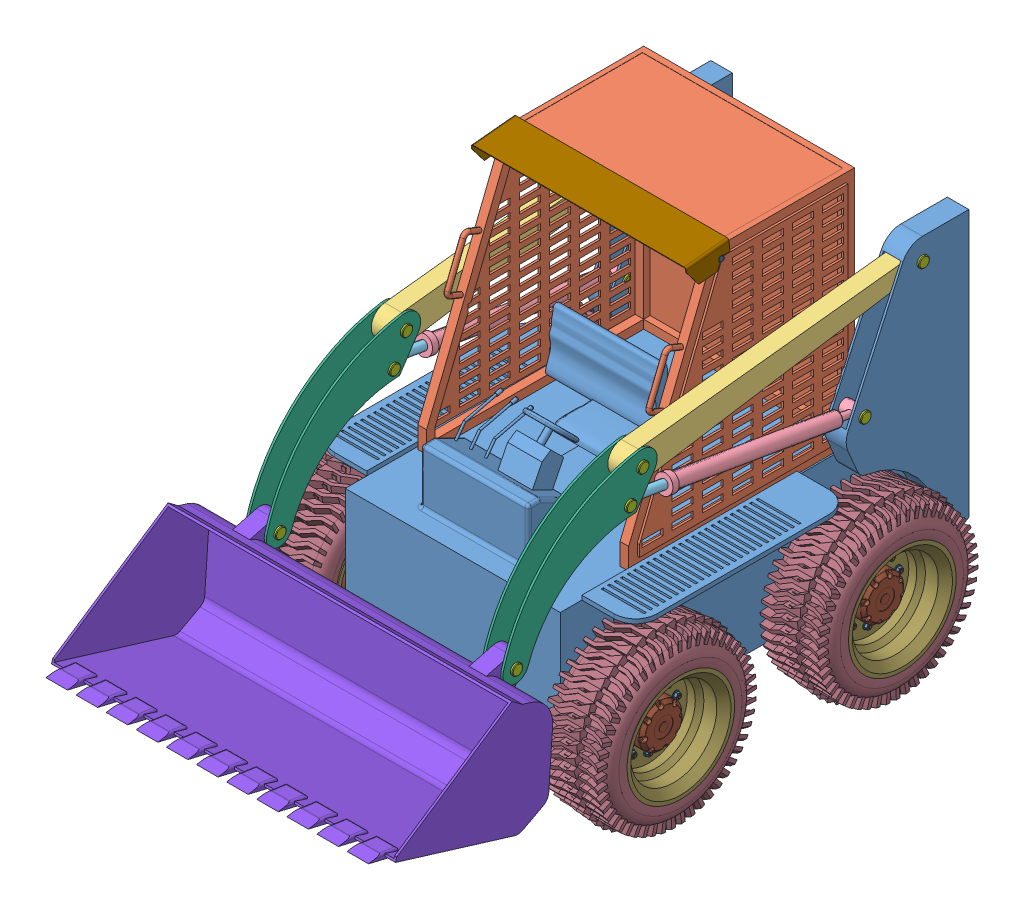
SolidWorks assembly MAINASSEM, configuration Default. Lengths in mm.
Overall size (1661.42 2117.38 2991.67).
82 component instances, 14 part files, 36 mates.
Components (placement in the parent):
- body-1: body [Default] at (611.6041 142.7188 2334.3513) size (1500 1375 1850)
- Part2-1: Part2 [Default] at (614.3973 1786.0912 2050.7348) size (1000 1100 1050)
- LIFTINGARM2-1: LIFTINGARM2 [Default] at (1161.6041 1247.7203 2057.6803) x (0 0.125849 -0.992049) z (1 0 0) size (1424.96 140 80)
- cylinderbody-1: cylinderbody [Default] at (1161.6041 1066.1236 1944.5095) x (0 -0.169943 -0.985454) z (0 -0.985454 0.169943) size (935 91.5 85)
- cylinder-1: cylinder [Default] at (1170.6016 1101.0933 2172.4592) x (0 -0.169943 -0.985454) z (1 0 0) size (960 60 80)
- LIFTING ARM-1: LIFTING ARM [Default] at (1206.6041 887.1212 2209.3761) x (0 -0.052276 -0.998633) z (1 0 0) size (690 680 10)
- LIFTING ARM-2: LIFTING ARM [Default] at (1116.6041 887.1212 2209.3761) x (0 -0.052276 -0.998633) z (1 0 0) size (690 680 10)
- pin-1: pin [Default] at (1155.3766 921.3702 1094.0266) x (0 -0.804682 0.593706) z (-1 0 0) size (50 50 120)
- pin-2: pin [Default] at (1167.8316 1418.2021 812.5835) x (0 0 -1) z (1 0 0) size (50 50 120)
- pin-3: pin [Default] at (1167.8316 1242.0493 2115.7317) x (0 0 -1) z (1 0 0) size (50 50 120)
- pin-4: pin [Default] at (1167.8316 1114.8408 2172.4592) x (0 0 -1) z (1 0 0) size (50 50 120)
- cylinderbody-2: cylinderbody [Default] at (61.6041 1057.6932 1945.9633) x (0 -0.169943 -0.985454) z (0 0.985454 -0.169943) size (935 91.5 85)
- LIFTINGARM2-2: LIFTINGARM2 [Default] at (61.6041 1247.7203 2057.6803) x (0 0.125849 -0.992049) z (1 0 0) size (1424.96 140 80)
- LIFTING ARM-3: LIFTING ARM [Default] at (16.6041 887.1212 2209.3761) x (0 -0.052276 -0.998633) z (1 0 0) size (690 680 10)
- LIFTING ARM-4: LIFTING ARM [Default] at (106.6041 887.1212 2209.3761) x (0 -0.052276 -0.998633) z (1 0 0) size (690 680 10)
- pin-5: pin [Default] at (67.8316 1242.0493 2115.7317) x (0 0 -1) z (1 0 0) size (50 50 120)
- pin-6: pin [Default] at (67.8316 1114.8408 2172.4592) x (0 0 -1) z (1 0 0) size (50 50 120)
- cylinder-2: cylinder [Default] at (52.6065 1101.0933 2172.4592) x (0 -0.169943 -0.985454) z (1 0 0) size (960 60 80)
- pin-7: pin [Default] at (55.3766 921.3702 1094.0266) x (0 -0.804682 0.593706) z (-1 0 0) size (50 50 120)
- pin-8: pin [Default] at (67.8316 1418.2021 812.5835) x (0 0 -1) z (1 0 0) size (50 50 120)
- bucket-1: bucket [Default] at (611.6041 787.1742 4757.017) x (1 0 0) z (0 0.292263 0.956338) size (1600 584.7 778.71)
- pin-9: pin [Default] at (1155.3766 722.0758 2703.7178) x (0 -0.000008 1) z (-1 0 0) size (50 50 120)
- pin-10: pin [Default] at (67.8316 722.0758 2703.7177) x (0 0 -1) z (1 0 0) size (50 50 120)
- cabin cap-1: cabin cap [Default] at (-264.117 1843.1629 1712.7348) x (1 0 0) z (0 -0.097432 0.995242) size (1000 100 200)
- cabinpin-1: cabinpin [Default] at (1152.5547 1805.3715 1646.3924) size (20.08 26 26)
- cabinpin-2: cabinpin [Default] at (70.2399 1772.6095 1623.9541) x (-1 0 0) z (0 -0.93241 0.361403) size (20.08 26 26)
- TYRE SUBASSEMBLY-1: TYRE SUBASSEMBLY [Default] at (1011.6041 44.44 2124.6318) x (1 0 0) z (0 0.62928 0.777179) size (370 785.47 785.35)
  - axle-1: axle [Default] at (218.9443 340.3251 180.7776) size (290.15 300 300)
  - rim-1: rim [Default] at (195.7643 350.8233 180.7776) size (310 500 500)
  - TYRE-1: TYRE [Default] at (277.7643 397.9842 180.7776) size (305.48 785.47 785.35)
  - hex flange nut_am-1: hex flange nut_am [B18.2.2.4M - Hex flange nut, M12 x 1.75 --N] at (292.7118 116.3804 57.1403) x (0 -0.380112 -0.92494) z (1 0 0) size (26 26 12)
  - hex flange nut_am-5: hex flange nut_am [B18.2.2.4M - Hex flange nut, M16 x 2 --N] at (296.7118 196.7248 57.1403) x (0 0 -1) z (1 0 0) size (34.5 34.5 16)
  - hex flange nut_am-6: hex flange nut_am [B18.2.2.4M - Hex flange nut, M16 x 2 --N] at (296.7118 261.7248 104.3655) x (0 0 -1) z (1 0 0) size (34.5 34.5 16)
  - hex flange nut_am-7: hex flange nut_am [B18.2.2.4M - Hex flange nut, M16 x 2 --N] at (296.7118 286.5526 180.7776) x (0 0 -1) z (1 0 0) size (34.5 34.5 16)
  - hex flange nut_am-8: hex flange nut_am [B18.2.2.4M - Hex flange nut, M16 x 2 --N] at (296.7118 261.7248 257.1897) x (0 0 -1) z (1 0 0) size (34.5 34.5 16)
  - hex flange nut_am-9: hex flange nut_am [B18.2.2.4M - Hex flange nut, M16 x 2 --N] at (296.7118 196.7248 304.415) x (0 0 -1) z (1 0 0) size (34.5 34.5 16)
  - hex flange nut_am-10: hex flange nut_am [B18.2.2.4M - Hex flange nut, M16 x 2 --N] at (296.7118 116.3804 304.415) x (0 0 -1) z (1 0 0) size (34.5 34.5 16)
  - hex flange nut_am-11: hex flange nut_am [B18.2.2.4M - Hex flange nut, M16 x 2 --N] at (296.7118 51.3804 257.1897) x (0 0 -1) z (1 0 0) size (34.5 34.5 16)
  - hex flange nut_am-12: hex flange nut_am [B18.2.2.4M - Hex flange nut, M16 x 2 --N] at (296.7118 26.5526 180.7776) x (0 0 -1) z (1 0 0) size (34.5 34.5 16)
  - hex flange nut_am-13: hex flange nut_am [B18.2.2.4M - Hex flange nut, M16 x 2 --N] at (296.7118 51.3804 104.3655) x (0 0 -1) z (1 0 0) size (34.5 34.5 16)
- TYRE SUBASSEMBLY-2: TYRE SUBASSEMBLY [Default] at (1011.6041 333.024 1369.7734) x (1 0 0) z (0 0.47024 -0.882539) size (370 785.47 785.35)
  - axle-1: axle [Default] at (218.9443 340.3251 180.7776) size (290.15 300 300)
  - rim-1: rim [Default] at (195.7643 350.8233 180.7776) size (310 500 500)
  - TYRE-1: TYRE [Default] at (277.7643 397.9842 180.7776) size (305.48 785.47 785.35)
  - hex flange nut_am-1: hex flange nut_am [B18.2.2.4M - Hex flange nut, M12 x 1.75 --N] at (292.7118 116.3804 57.1403) x (0 -0.380112 -0.92494) z (1 0 0) size (26 26 12)
  - hex flange nut_am-5: hex flange nut_am [B18.2.2.4M - Hex flange nut, M16 x 2 --N] at (296.7118 196.7248 57.1403) x (0 0 -1) z (1 0 0) size (34.5 34.5 16)
  - hex flange nut_am-6: hex flange nut_am [B18.2.2.4M - Hex flange nut, M16 x 2 --N] at (296.7118 261.7248 104.3655) x (0 0 -1) z (1 0 0) size (34.5 34.5 16)
  - hex flange nut_am-7: hex flange nut_am [B18.2.2.4M - Hex flange nut, M16 x 2 --N] at (296.7118 286.5526 180.7776) x (0 0 -1) z (1 0 0) size (34.5 34.5 16)
  - hex flange nut_am-8: hex flange nut_am [B18.2.2.4M - Hex flange nut, M16 x 2 --N] at (296.7118 261.7248 257.1897) x (0 0 -1) z (1 0 0) size (34.5 34.5 16)
  - hex flange nut_am-9: hex flange nut_am [B18.2.2.4M - Hex flange nut, M16 x 2 --N] at (296.7118 196.7248 304.415) x (0 0 -1) z (1 0 0) size (34.5 34.5 16)
  - hex flange nut_am-10: hex flange nut_am [B18.2.2.4M - Hex flange nut, M16 x 2 --N] at (296.7118 116.3804 304.415) x (0 0 -1) z (1 0 0) size (34.5 34.5 16)
  - hex flange nut_am-11: hex flange nut_am [B18.2.2.4M - Hex flange nut, M16 x 2 --N] at (296.7118 51.3804 257.1897) x (0 0 -1) z (1 0 0) size (34.5 34.5 16)
  - hex flange nut_am-12: hex flange nut_am [B18.2.2.4M - Hex flange nut, M16 x 2 --N] at (296.7118 26.5526 180.7776) x (0 0 -1) z (1 0 0) size (34.5 34.5 16)
  - hex flange nut_am-13: hex flange nut_am [B18.2.2.4M - Hex flange nut, M16 x 2 --N] at (296.7118 51.3804 104.3655) x (0 0 -1) z (1 0 0) size (34.5 34.5 16)
- TYRE SUBASSEMBLY-4: TYRE SUBASSEMBLY [Default] at (211.6041 287.7784 1927.6012) x (-1 0 0) z (0 0.62928 0.777179) size (370 785.47 785.35)
  - axle-1: axle [Default] at (218.9443 340.3251 180.7776) size (290.15 300 300)
  - rim-1: rim [Default] at (195.7643 350.8233 180.7776) size (310 500 500)
  - TYRE-1: TYRE [Default] at (277.7643 397.9842 180.7776) size (305.48 785.47 785.35)
  - hex flange nut_am-1: hex flange nut_am [B18.2.2.4M - Hex flange nut, M12 x 1.75 --N] at (292.7118 116.3804 57.1403) x (0 -0.380112 -0.92494) z (1 0 0) size (26 26 12)
  - hex flange nut_am-5: hex flange nut_am [B18.2.2.4M - Hex flange nut, M16 x 2 --N] at (296.7118 196.7248 57.1403) x (0 0 -1) z (1 0 0) size (34.5 34.5 16)
  - hex flange nut_am-6: hex flange nut_am [B18.2.2.4M - Hex flange nut, M16 x 2 --N] at (296.7118 261.7248 104.3655) x (0 0 -1) z (1 0 0) size (34.5 34.5 16)
  - hex flange nut_am-7: hex flange nut_am [B18.2.2.4M - Hex flange nut, M16 x 2 --N] at (296.7118 286.5526 180.7776) x (0 0 -1) z (1 0 0) size (34.5 34.5 16)
  - hex flange nut_am-8: hex flange nut_am [B18.2.2.4M - Hex flange nut, M16 x 2 --N] at (296.7118 261.7248 257.1897) x (0 0 -1) z (1 0 0) size (34.5 34.5 16)
  - hex flange nut_am-9: hex flange nut_am [B18.2.2.4M - Hex flange nut, M16 x 2 --N] at (296.7118 196.7248 304.415) x (0 0 -1) z (1 0 0) size (34.5 34.5 16)
  - hex flange nut_am-10: hex flange nut_am [B18.2.2.4M - Hex flange nut, M16 x 2 --N] at (296.7118 116.3804 304.415) x (0 0 -1) z (1 0 0) size (34.5 34.5 16)
  - hex flange nut_am-11: hex flange nut_am [B18.2.2.4M - Hex flange nut, M16 x 2 --N] at (296.7118 51.3804 257.1897) x (0 0 -1) z (1 0 0) size (34.5 34.5 16)
  - hex flange nut_am-12: hex flange nut_am [B18.2.2.4M - Hex flange nut, M16 x 2 --N] at (296.7118 26.5526 180.7776) x (0 0 -1) z (1 0 0) size (34.5 34.5 16)
  - hex flange nut_am-13: hex flange nut_am [B18.2.2.4M - Hex flange nut, M16 x 2 --N] at (296.7118 51.3804 104.3655) x (0 0 -1) z (1 0 0) size (34.5 34.5 16)
- TYRE SUBASSEMBLY-5: TYRE SUBASSEMBLY [Default] at (211.6041 56.697 1222.539) x (-1 0 0) z (0 0.47024 -0.882539) size (370 785.47 785.35)
  - axle-1: axle [Default] at (218.9443 340.3251 180.7776) size (290.15 300 300)
  - rim-1: rim [Default] at (195.7643 350.8233 180.7776) size (310 500 500)
  - TYRE-1: TYRE [Default] at (277.7643 397.9842 180.7776) size (305.48 785.47 785.35)
  - hex flange nut_am-1: hex flange nut_am [B18.2.2.4M - Hex flange nut, M12 x 1.75 --N] at (292.7118 116.3804 57.1403) x (0 -0.380112 -0.92494) z (1 0 0) size (26 26 12)
  - hex flange nut_am-5: hex flange nut_am [B18.2.2.4M - Hex flange nut, M16 x 2 --N] at (296.7118 196.7248 57.1403) x (0 0 -1) z (1 0 0) size (34.5 34.5 16)
  - hex flange nut_am-6: hex flange nut_am [B18.2.2.4M - Hex flange nut, M16 x 2 --N] at (296.7118 261.7248 104.3655) x (0 0 -1) z (1 0 0) size (34.5 34.5 16)
  - hex flange nut_am-7: hex flange nut_am [B18.2.2.4M - Hex flange nut, M16 x 2 --N] at (296.7118 286.5526 180.7776) x (0 0 -1) z (1 0 0) size (34.5 34.5 16)
  - hex flange nut_am-8: hex flange nut_am [B18.2.2.4M - Hex flange nut, M16 x 2 --N] at (296.7118 261.7248 257.1897) x (0 0 -1) z (1 0 0) size (34.5 34.5 16)
  - hex flange nut_am-9: hex flange nut_am [B18.2.2.4M - Hex flange nut, M16 x 2 --N] at (296.7118 196.7248 304.415) x (0 0 -1) z (1 0 0) size (34.5 34.5 16)
  - hex flange nut_am-10: hex flange nut_am [B18.2.2.4M - Hex flange nut, M16 x 2 --N] at (296.7118 116.3804 304.415) x (0 0 -1) z (1 0 0) size (34.5 34.5 16)
  - hex flange nut_am-11: hex flange nut_am [B18.2.2.4M - Hex flange nut, M16 x 2 --N] at (296.7118 51.3804 257.1897) x (0 0 -1) z (1 0 0) size (34.5 34.5 16)
  - hex flange nut_am-12: hex flange nut_am [B18.2.2.4M - Hex flange nut, M16 x 2 --N] at (296.7118 26.5526 180.7776) x (0 0 -1) z (1 0 0) size (34.5 34.5 16)
  - hex flange nut_am-13: hex flange nut_am [B18.2.2.4M - Hex flange nut, M16 x 2 --N] at (296.7118 51.3804 104.3655) x (0 0 -1) z (1 0 0) size (34.5 34.5 16)
Mates (geometry in assembly coordinates):
- Coincident2: coincident anti-aligned: plane of body-1 through (1111.6041 731.3066 2396.6129) normal (0 1 0); plane of Part2-1 through (1104.3973 731.3066 1021.3924) normal (0 -1 0)
- Concentric1: concentric anti-aligned: cylinder of body-1 through (-128.3959 1404.4546 812.5835) axis (1 0 0) radius 20; cylinder of LIFTINGARM2-1 through (1201.6041 1404.4546 812.5835) axis (-1 0 0) radius 20
- Coincident3: coincident anti-aligned: plane of body-1 through (1121.6041 142.7188 2334.3513) normal (1 0 0); plane of LIFTINGARM2-1 through (1121.6041 1228.3018 2115.7317) normal (-1 0 0)
- Concentric2: concentric anti-aligned: cylinder of body-1 through (-128.3959 913.2082 1082.9643) axis (1 0 0) radius 15; cylinder of cylinderbody-1 through (1201.6041 913.2082 1082.9643) axis (-1 0 0) radius 15
- Coincident4: coincident anti-aligned: plane of body-1 through (1121.6041 142.7188 2334.3513) normal (1 0 0); plane of cylinderbody-1 through (1121.6041 913.2082 1082.9643) normal (-1 0 0)
- Concentric3: concentric anti-aligned: cylinder of cylinderbody-1 through (1170.6016 1067.0067 1974.8) axis (0 -0.169943 -0.985454) radius 20; cylinder of cylinder-1 through (1170.6016 943.0463 1255.9871) axis (0 0.169943 0.985454) radius 20
- Concentric7: concentric aligned: cylinder of LIFTINGARM2-1 through (1201.6041 1228.3018 2115.7317) axis (-1 0 0) radius 25; cylinder of LIFTING ARM-1 through (1211.6041 1228.3018 2115.7317) axis (-1 0 0) radius 20
- Coincident7: coincident anti-aligned: plane of LIFTINGARM2-1 through (1201.6041 1228.3018 2115.7317) normal (1 0 0); plane of LIFTING ARM-1 through (1201.6041 522.2438 2003.0055) normal (-1 0 0)
- Concentric8: concentric aligned: cylinder of cylinder-1 through (1210.6016 1101.0933 2172.4592) axis (-1 0 0) radius 15; cylinder of LIFTING ARM-1 through (1211.6041 1101.0933 2172.4592) axis (-1 0 0) radius 15
- Concentric10: concentric aligned: cylinder of LIFTINGARM2-1 through (1201.6041 1228.3018 2115.7317) axis (-1 0 0) radius 25; cylinder of LIFTING ARM-2 through (1121.6041 1228.3018 2115.7317) axis (-1 0 0) radius 20
- Coincident8: coincident anti-aligned: plane of LIFTINGARM2-1 through (1121.6041 1228.3018 2115.7317) normal (-1 0 0); plane of LIFTING ARM-2 through (1121.6041 522.2438 2003.0055) normal (1 0 0)
- Concentric11: concentric aligned: cylinder of cylinder-1 through (1210.6016 1101.0933 2172.4592) axis (-1 0 0) radius 15; cylinder of LIFTING ARM-2 through (1121.6041 1101.0933 2172.4592) axis (-1 0 0) radius 15
- Concentric12: concentric anti-aligned: cylinder of body-1 through (-128.3959 913.2082 1082.9643) axis (1 0 0) radius 15; cylinder of pin-1 through (1101.6041 913.2082 1082.9643) axis (-1 0 0) radius 15
- Coincident10: coincident anti-aligned: plane of body-1 through (1211.6041 199.3179 735.3276) normal (1 0 0); plane of pin-1 through (1211.6041 928.0509 1103.0813) normal (-1 0 0)
- Concentric13: concentric anti-aligned: cylinder of LIFTINGARM2-1 through (1201.6041 1404.4546 812.5835) axis (-1 0 0) radius 20; cylinder of pin-2 through (1221.6041 1404.4546 812.5835) axis (1 0 0) radius 15
- Coincident11: coincident anti-aligned: plane of body-1 through (1211.6041 199.3179 735.3276) normal (1 0 0); plane of pin-2 through (1211.6041 1419.4546 812.5835) normal (-1 0 0)
- Concentric14: concentric anti-aligned: cylinder of LIFTINGARM2-1 through (1201.6041 1228.3018 2115.7317) axis (-1 0 0) radius 25; cylinder of pin-3 through (1221.6041 1228.3018 2115.7317) axis (1 0 0) radius 15
- Coincident12: coincident anti-aligned: plane of LIFTING ARM-1 through (1211.6041 522.2438 2003.0055) normal (1 0 0); plane of pin-3 through (1211.6041 1243.3018 2115.7317) normal (-1 0 0)
- Concentric15: concentric anti-aligned: cylinder of cylinder-1 through (1210.6016 1101.0933 2172.4592) axis (-1 0 0) radius 15; cylinder of pin-4 through (1221.6041 1101.0933 2172.4592) axis (1 0 0) radius 15
- Coincident13: coincident anti-aligned: plane of LIFTING ARM-1 through (1211.6041 522.2438 2003.0055) normal (1 0 0); plane of pin-4 through (1211.6041 1116.0933 2172.4592) normal (-1 0 0)
- Concentric16: concentric aligned: cylinder of LIFTING ARM-4 through (111.6041 708.3283 2703.7177) axis (-1 0 0) radius 20; cylinder of bucket-1 through (101.6041 708.3283 2703.7177) axis (-1 0 0) radius 20
- Coincident14: coincident anti-aligned: plane of LIFTING ARM-4 through (101.6041 522.2438 2003.0055) normal (-1 0 0); plane of bucket-1 through (101.6041 602.8718 2871.8811) normal (1 0 0)
- Concentric17: concentric anti-aligned: cylinder of bucket-1 through (1121.6041 708.3283 2703.7177) axis (1 0 0) radius 20; cylinder of pin-9 through (1101.6041 708.3283 2703.7177) axis (-1 0 0) radius 15
- Coincident15: coincident anti-aligned: plane of LIFTING ARM-1 through (1211.6041 522.2438 2003.0055) normal (1 0 0); plane of pin-9 through (1211.6041 733.3283 2703.7179) normal (-1 0 0)
- Concentric18: concentric anti-aligned: cylinder of bucket-1 through (101.6041 708.3283 2703.7177) axis (-1 0 0) radius 20; cylinder of pin-10 through (121.6041 708.3283 2703.7177) axis (1 0 0) radius 15
- Coincident16: coincident anti-aligned: plane of LIFTING ARM-4 through (111.6041 522.2438 2003.0055) normal (1 0 0); plane of pin-10 through (111.6041 723.3283 2703.7177) normal (-1 0 0)
- Concentric19: concentric aligned: cylinder of Part2-1 through (114.3973 1781.3066 1646.3924) axis (1 0 0) radius 10; cylinder of cabin cap-1 through (111.3973 1781.3066 1646.3924) axis (1 0 0) radius 10
- Coincident17: coincident anti-aligned: plane of Part2-1 through (114.3973 1786.0912 2050.7348) normal (-1 0 0); plane of cabin cap-1 through (114.3973 1822.4464 1811.1847) normal (1 0 0)
- Concentric20: concentric anti-aligned: cylinder of cabin cap-1 through (111.3973 1781.3066 1646.3924) axis (1 0 0) radius 10; cylinder of cabinpin-1 through (1095.3973 1781.3066 1646.3924) axis (-1 0 0) radius 10
- Coincident18: coincident anti-aligned: plane of cabin cap-1 through (1111.3973 1825.4321 1811.477) normal (1 0 0); plane of cabinpin-1 through (1111.3973 1791.3066 1646.3924) normal (-1 0 0)
- Concentric22: concentric aligned: cylinder of Part2-1 through (114.3973 1781.3066 1646.3924) axis (1 0 0) radius 10; cylinder of cabinpin-2 through (127.3973 1781.3066 1646.3924) axis (1 0 0) radius 10
- Coincident20: coincident anti-aligned: plane of cabin cap-1 through (111.3973 1825.4321 1811.477) normal (-1 0 0); plane of cabinpin-2 through (111.3973 1777.6926 1637.0683) normal (1 0 0)
- Concentric23: concentric anti-aligned: cylinder of body-1 through (1111.6041 279.8691 2166.6129) axis (-1 0 0) radius 53.1312; cylinder of TYRE SUBASSEMBLY-1/axle-1 through (1072.3159 279.8691 2166.6129) axis (1 0 0) radius 40
- Distance2: distance = 400 mm aligned: plane of body-1 through (611.6041 142.7188 2334.3513) normal (1 0 0); plane of TYRE SUBASSEMBLY-1
- Concentric25: concentric anti-aligned: cylinder of body-1 through (1111.6041 279.8691 1136.6129) axis (-1 0 0) radius 53.1312; cylinder of TYRE SUBASSEMBLY-2/axle-1 through (1072.3159 279.8691 1136.6129) axis (1 0 0) radius 40
- Distance4: distance = 400 mm aligned: plane of body-1 through (611.6041 142.7188 2334.3513) normal (1 0 0); plane of TYRE SUBASSEMBLY-2
